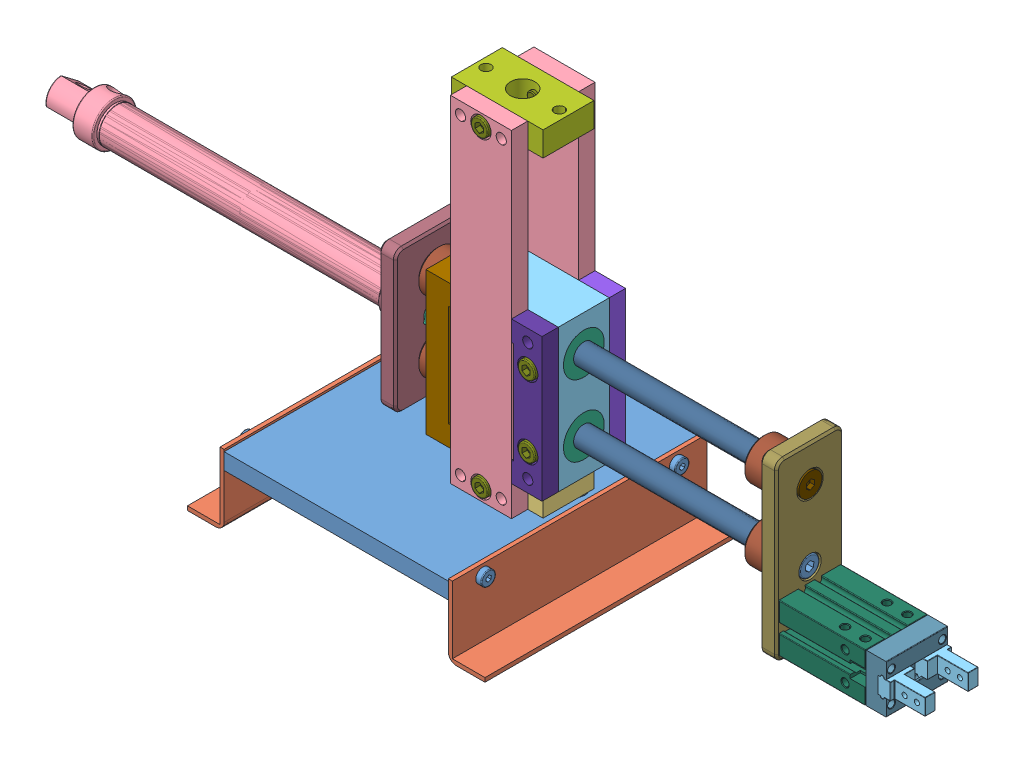
SolidWorks assembly S4, configuration Default. Lengths in mm.
Overall size (436.7 199 125).
52 component instances, 24 part files, 126 mates.
Components (placement in the parent):
- tam de lon-1: tam de lon [Default] at (42.5889 56.6685 101.1963) size (110 8 125)
- khoi do-1: khoi do [Default] at (98.4472 49.4552 163.6963) x (0 0 -1) z (-1 0 0) size (125 35 18)
- khoi do-2: khoi do [Default] at (-13.2695 49.4552 38.6963) x (0 0 1) z (1 0 0) size (125 35 18)
- mieng dem duoi-1: mieng dem duoi [Default] at (71.5889 64.6685 101.1963) size (45 12 25)
- thanh dan huong lon x2-1: thanh dan huong lon x2 [Default] at (71.5889 147.1685 113.6963) x (1 0 0) z (0 -1 0) size (30 8 165)
- thanh dan huong lon x2-2: thanh dan huong lon x2 [Default] at (71.5889 147.1685 88.6963) x (1 0 0) z (0 1 0) size (30 8 165)
- con truot s4 -1: con truot s4  [Default] at (79.0889 79.5805 101.1963) x (-1 0 0) z (0 0 -1) size (45 70 25)
- bac lot-1: bac lot [Default] at (101.5889 97.0805 101.1963) x (0 1 0) z (0 0 1) size (20 12 20)
- bac lot-2: bac lot [Default] at (101.5889 132.0805 101.1963) x (0 1 0) z (0 0 1) size (20 12 20)
- bac lot-3: bac lot [Default] at (56.5889 132.0805 101.1963) x (0 0.381849 -0.924225) z (0 -0.924225 -0.381849) size (20 12 20)
- bac lot-4: bac lot [Default] at (56.5889 97.0805 101.1963) x (0 0.381849 -0.924225) z (0 -0.924225 -0.381849) size (20 12 20)
- mieng dem tren-1: mieng dem tren [Default] at (71.5889 217.6685 101.1963) size (45 12 25)
- thanh dan huong so 2 s4-3: thanh dan huong so 2 s4 [Default] at (94.0889 114.5805 88.6963) x (-1 0 0) z (0 -1 0) size (15 8 70)
- tam dan huong-4: tam dan huong [Default] at (44.5889 114.5805 101.1963) x (0 -1 0) z (0 0 1) size (70 12 41)
- chot dan huong-1: chot dan huong [Default] at (204.5889 132.0805 101.1963) x (0 0.988897 -0.148604) z (0 0.148604 0.988897) size (10 175 10)
- chot dan huong-2: chot dan huong [Default] at (204.5889 97.0805 101.1963) x (0 0.324021 0.94605) z (0 -0.94605 0.324021) size (10 175 10)
- bac chan-1: bac chan [Default] at (204.5889 132.0805 101.1963) x (0 0.942027 0.335537) z (0 -0.335537 0.942027) size (20 15 20)
- bac chan-2: bac chan [Default] at (204.5889 97.0805 101.1963) x (0 1 0) z (0 0 1) size (20 15 20)
- bac chan-3: bac chan [Default] at (44.5889 132.0805 101.1963) x (0 -0.757955 0.652306) z (0 -0.652306 -0.757955) size (20 15 20)
- bac chan-4: bac chan [Default] at (44.5889 97.0805 101.1963) x (0 0.99939 -0.03491) z (0 0.03491 0.99939) size (20 15 20)
- ban canh truoc-1: ban canh truoc [Default] at (204.5889 106.5805 101.1963) x (0 0 -1) z (0 -1 0) size (33 8 86)
- ban canh sau-1: ban canh sau [Default] at (29.5889 114.5805 101.1963) x (0 0 -1) z (0 1 0) size (41 8 70)
- NMHZ2-16D-2: NMHZ2-16D [Default] at (197.6009 76.0227 123.6032) x (0 0 -1) z (1 0 0) size (30.6 23.6 52.5)
  - NMHZ2-16D Slipway-1: NMHZ2-16D Slipway [Default] at (22.4069 2.6078 57.488) size (30.1 23.6 10)
  - NMHZ2-16D cylinder-2: NMHZ2-16D cylinder [Default] at (22.4069 2.6078 14.988) size (30.6 23.6 42.5)
- socket head cap screw_din-2: socket head cap screw_din [DIN 912 M5 x 16 --- 16N] at (94.5889 132.0805 79.8963) x (0 0 1) z (-1 0 0) size (21 8.5 8.5)
- socket head cap screw_din-5: socket head cap screw_din [DIN 912 M5 x 16 --- 16N] at (94.5889 97.0805 79.8963) x (0 0 1) z (-1 0 0) size (21 8.5 8.5)
- socket head cap screw_din-6: socket head cap screw_din [DIN 912 M5 x 16 --- 16N] at (71.5889 70.6685 79.8963) x (0 0 1) z (-1 0 0) size (21 8.5 8.5)
- socket head cap screw_din-9: socket head cap screw_din [DIN 912 M5 x 8 --- 8N] at (71.5889 70.6685 122.4963) x (0 0 -1) z (1 0 0) size (13 8.5 8.5)
- socket head cap screw_din-10: socket head cap screw_din [DIN 912 M5 x 8 --- 8N] at (45.2889 85.5805 108.6963) size (13 8.5 8.5)
- socket head cap screw_din-11: socket head cap screw_din [DIN 912 M5 x 8 --- 8N] at (45.2889 143.5805 93.6963) size (13 8.5 8.5)
- thanh dan huong s4-1: thanh dan huong s4 [Default] at (94.0889 114.5805 113.6963) x (-1 0 0) z (0 1 0) size (15 8 70)
- socket head cap screw_din-13: socket head cap screw_din [DIN 912 M5 x 12 --- 12N] at (94.5889 97.0805 122.4963) x (0 0 -1) z (1 0 0) size (17 8.5 8.5)
- socket head cap screw_din-14: socket head cap screw_din [DIN 912 M5 x 12 --- 12N] at (94.5889 132.0805 122.4963) x (0 0 -1) z (1 0 0) size (17 8.5 8.5)
- socket head cap screw_din-17: socket head cap screw_din [DIN 912 M5 x 12 --- 12N] at (71.5889 223.6685 79.8963) x (0 0 1) z (-0.154025 0.988067 0) size (17 8.5 8.5)
- socket head cap screw_din-18: socket head cap screw_din [DIN 912 M5 x 12 --- 12N] at (71.5889 223.6685 122.4963) x (0 0 -1) z (1 0 0) size (17 8.5 8.5)
- socket csink head cap screw 10642_din-2: socket csink head cap screw 10642_din [EN ISO 10642 - M6 x 8 - 8N] at (21.3689 132.0805 101.1963) x (1 0 0) z (0 0.02259 0.999745) size (8 11.34 11.34)
- socket csink head cap screw 10642_din-3: socket csink head cap screw 10642_din [EN ISO 10642 - M6 x 8 - 8N] at (212.8089 132.0805 101.1963) x (-1 0 0) z (0 -0.022602 -0.999745) size (8 11.34 11.34)
- socket head thin cap screw_din-2: socket head thin cap screw_din [DIN 7984 - M6 x 10 --- 7N] at (212.3889 97.0805 101.1963) x (-1 0 0) z (0 0.924225 0.381849) size (14 10 10)
- socket head thin cap screw_din-4: socket head thin cap screw_din [DIN 7984 - M6 x 10 --- 7N] at (21.7889 97.0805 101.1963) size (14 10 10)
- socket head thin cap screw_din-5: socket head thin cap screw_din [DIN 7984 - M4 x 6 --- 3.9N] at (-17.2111 60.6685 53.6963) size (8.8 7 7)
- socket head thin cap screw_din-6: socket head thin cap screw_din [DIN 7984 - M4 x 6 --- 3.9N] at (-17.2111 60.6685 148.6963) size (8.8 7 7)
- socket head thin cap screw_din-7: socket head thin cap screw_din [DIN 7984 - M4 x 6 --- 3.9N] at (102.3889 60.6685 53.6963) x (-1 0 0) z (0 0.924225 0.381849) size (8.8 7 7)
- socket head thin cap screw_din-8: socket head thin cap screw_din [DIN 7984 - M4 x 6 --- 3.9N] at (102.3889 60.6685 148.6963) x (-1 0 0) z (0 0.924225 0.381849) size (8.8 7 7)
- socket head thin cap screw_din-10: socket head thin cap screw_din [DIN 7984 - M4 x 12 --- 9.9N] at (206.1889 71.2805 112.1963) size (14.8 7 7)
- socket head thin cap screw_din-11: socket head thin cap screw_din [DIN 7984 - M4 x 12 --- 9.9N] at (206.1889 86.2805 90.1963) size (14.8 7 7)
- Rod-1: Rod [Default] at (-92.4392 114.5805 101.1963) x (0 0.871767 -0.48992) z (0 -0.48992 -0.871767) size (6.2 165 6.2)
- Nut 5-1: Nut 5 [Default] at (55.0889 114.5805 101.1963) x (0 0.12782 0.991797) z (0 0.991797 -0.12782) size (11.32 3 9.8)
- 16 X 100 Cylinder bore-2: 16 X 100 Cylinder bore [Default] at (-58.6111 114.5805 101.1963) x (0 0.79605 -0.605231) z (-1 0 0) size (21.5 21.5 192)
- NMHZ2-16D air claw-1: NMHZ2-16D air claw [Default] at (263.0889 78.6305 98.1463) x (0 0 -1) z (1 0 0) size (12 10 21)
- NMHZ2-16D air claw-2: NMHZ2-16D air claw [Default] at (263.0889 78.6305 104.2463) x (0 0 1) z (1 0 0) size (12 10 21)
- hex nut style 2 gradeab_din-2: hex nut style 2 gradeab_din [Hexagon Nut ISO 4033 - M8 - W - N] at (37.0889 114.5805 101.1963) x (0 0.684808 -0.728723) z (1 0 0) size (13 15.01 7.5)
Mates (geometry in assembly coordinates):
- Parallel1: parallel anti-aligned: plane of tam de lon-1 through (42.5889 64.6685 101.1963) normal (0 1 0); plane of khoi do-1 through (97.5889 30.6685 38.6963) normal (0 -1 0)
- Parallel2: parallel anti-aligned: plane of tam de lon-1 through (97.5889 64.6685 38.6963) normal (1 0 0); plane of khoi do-1 through (97.5889 30.6685 38.6963) normal (-1 0 0)
- Concentric1: concentric aligned: cylinder of tam de lon-1 through (82.5889 60.6685 53.6963) axis (1 0 0) radius 2.5; cylinder of khoi do-1 through (-25.4111 60.6685 53.6963) axis (1 0 0) radius 2.5
- Coincident1: coincident anti-aligned: plane of tam de lon-1 through (97.5889 64.6685 38.6963) normal (1 0 0); plane of khoi do-1 through (97.5889 30.6685 38.6963) normal (-1 0 0)
- Parallel3: parallel anti-aligned: plane of tam de lon-1 through (42.5889 64.6685 101.1963) normal (0 1 0); plane of khoi do-2 through (-12.4111 30.6685 163.6963) normal (0 -1 0)
- Parallel4: parallel anti-aligned: plane of tam de lon-1 through (-12.4111 64.6685 38.6963) normal (-1 0 0); plane of khoi do-2 through (-12.4111 30.6685 163.6963) normal (1 0 0)
- Concentric2: concentric aligned: cylinder of tam de lon-1 through (2.5889 60.6685 148.6963) axis (-1 0 0) radius 2.5; cylinder of khoi do-2 through (110.5889 60.6685 148.6963) axis (-1 0 0) radius 2.5
- Coincident2: coincident anti-aligned: plane of tam de lon-1 through (-12.4111 64.6685 38.6963) normal (-1 0 0); plane of khoi do-2 through (-12.4111 30.6685 163.6963) normal (1 0 0)
- Concentric3: concentric aligned: cylinder of tam de lon-1 through (89.5889 56.6685 93.6963) axis (0 1 0) radius 2.75; cylinder of mieng dem duoi-1 through (89.5889 64.6685 93.6963) axis (0 1 0) radius 2.5
- Concentric4: concentric aligned: cylinder of tam de lon-1 through (53.5889 56.6685 108.6963) axis (0 1 0) radius 2.75; cylinder of mieng dem duoi-1 through (53.5889 64.6685 108.6963) axis (0 1 0) radius 2.5
- Coincident3: coincident anti-aligned: plane of tam de lon-1 through (42.5889 64.6685 101.1963) normal (0 1 0); plane of mieng dem duoi-1 through (71.5889 64.6685 101.1963) normal (0 -1 0)
- Parallel6: parallel anti-aligned: plane of mieng dem duoi-1 through (71.5889 76.6685 101.1963) normal (0 1 0); plane of thanh dan huong lon x2-1 through (56.5889 64.6685 121.6963) normal (0 -1 0)
- Parallel7: parallel anti-aligned: plane of mieng dem duoi-1 through (49.0889 76.6685 113.6963) normal (0 0 1); plane of thanh dan huong lon x2-1 through (71.5889 147.1685 113.6963) normal (0 0 -1)
- Concentric5: concentric anti-aligned: cylinder of mieng dem duoi-1 through (81.5889 70.6685 160.6963) axis (0 0 -1) radius 2.5; cylinder of thanh dan huong lon x2-1 through (81.5889 70.6685 80.4963) axis (0 0 1) radius 2.5
- Coincident4: coincident anti-aligned: plane of mieng dem duoi-1 through (49.0889 76.6685 113.6963) normal (0 0 1); plane of thanh dan huong lon x2-1 through (71.5889 147.1685 113.6963) normal (0 0 -1)
- Parallel8: parallel anti-aligned: plane of mieng dem duoi-1 through (71.5889 76.6685 101.1963) normal (0 1 0); plane of thanh dan huong lon x2-2 through (56.5889 64.6685 80.6963) normal (0 -1 0)
- Parallel9: parallel anti-aligned: plane of mieng dem duoi-1 through (49.0889 76.6685 88.6963) normal (0 0 -1); plane of thanh dan huong lon x2-2 through (71.5889 147.1685 88.6963) normal (0 0 1)
- Concentric6: concentric aligned: cylinder of mieng dem duoi-1 through (81.5889 70.6685 160.6963) axis (0 0 -1) radius 2.5; cylinder of thanh dan huong lon x2-2 through (81.5889 70.6685 121.8963) axis (0 0 -1) radius 2.5
- Coincident5: coincident anti-aligned: plane of mieng dem duoi-1 through (49.0889 76.6685 88.6963) normal (0 0 -1); plane of thanh dan huong lon x2-2 through (71.5889 147.1685 88.6963) normal (0 0 1)
- Parallel10: parallel anti-aligned: plane of mieng dem duoi-1 through (94.0889 76.6685 88.6963) normal (1 0 0); plane of con truot s4 -1 through (56.5889 149.5805 113.6963) normal (-1 0 0)
- Parallel11: parallel aligned: plane of mieng dem duoi-1 through (71.5889 76.6685 101.1963) normal (0 1 0); plane of con truot s4 -1 through (79.0889 149.5805 101.1963) normal (0 1 0)
- Coincident6: coincident anti-aligned: plane of thanh dan huong lon x2-2 through (71.5889 147.1685 88.6963) normal (0 0 1); plane of con truot s4 -1 through (101.5889 149.5805 88.6963) normal (0 0 -1)
- Concentric7: concentric anti-aligned: cylinder of con truot s4 -1 through (126.5889 97.0805 101.1963) axis (-1 0 0) radius 6; cylinder of bac lot-1 through (89.5889 97.0805 101.1963) axis (1 0 0) radius 6
- Coincident14: coincident anti-aligned: plane of con truot s4 -1 through (99.5889 97.0805 101.1963) normal (1 0 0); plane of bac lot-1 through (99.5889 97.0805 101.1963) normal (-1 0 0)
- Concentric8: concentric anti-aligned: cylinder of con truot s4 -1 through (126.5889 132.0805 101.1963) axis (-1 0 0) radius 6; cylinder of bac lot-2 through (89.5889 132.0805 101.1963) axis (1 0 0) radius 6
- Coincident15: coincident anti-aligned: plane of con truot s4 -1 through (99.5889 132.0805 101.1963) normal (1 0 0); plane of bac lot-2 through (99.5889 132.0805 101.1963) normal (-1 0 0)
- Concentric9: concentric aligned: cylinder of con truot s4 -1 through (126.5889 132.0805 101.1963) axis (-1 0 0) radius 6; cylinder of bac lot-3 through (68.5889 132.0805 101.1963) axis (-1 0 0) radius 6
- Coincident16: coincident anti-aligned: plane of con truot s4 -1 through (58.5889 132.0805 101.1963) normal (-1 0 0); plane of bac lot-3 through (58.5889 132.0805 101.1963) normal (1 0 0)
- Concentric10: concentric aligned: cylinder of con truot s4 -1 through (126.5889 97.0805 101.1963) axis (-1 0 0) radius 6; cylinder of bac lot-4 through (68.5889 97.0805 101.1963) axis (-1 0 0) radius 6
- Coincident18: coincident anti-aligned: plane of con truot s4 -1 through (58.5889 97.0805 101.1963) normal (-1 0 0); plane of bac lot-4 through (58.5889 97.0805 101.1963) normal (1 0 0)
- Parallel23: parallel aligned: plane of thanh dan huong lon x2-2 through (56.5889 229.6685 80.6963) normal (0 1 0); plane of mieng dem tren-1 through (71.5889 229.6685 101.1963) normal (0 1 0)
- Concentric12: concentric aligned: cylinder of thanh dan huong lon x2-2 through (61.5889 223.6685 121.8963) axis (0 0 -1) radius 2.5; cylinder of mieng dem tren-1 through (61.5889 223.6685 160.6963) axis (0 0 -1) radius 2.5
- Coincident21: coincident anti-aligned: plane of thanh dan huong lon x2-2 through (71.5889 147.1685 88.6963) normal (0 0 1); plane of mieng dem tren-1 through (49.0889 229.6685 88.6963) normal (0 0 -1)
- Parallel38: parallel aligned: plane of con truot s4 -1 through (79.0889 149.5805 101.1963) normal (0 1 0); plane of thanh dan huong so 2 s4-3 through (101.5889 149.5805 80.6963) normal (0 1 0)
- Parallel39: parallel anti-aligned: plane of con truot s4 -1 through (101.5889 149.5805 88.6963) normal (0 0 -1); plane of thanh dan huong so 2 s4-3 through (94.0889 114.5805 88.6963) normal (0 0 1)
- Coincident32: coincident aligned: plane of con truot s4 -1 through (79.0889 149.5805 101.1963) normal (0 1 0); plane of thanh dan huong so 2 s4-3 through (101.5889 149.5805 80.6963) normal (0 1 0)
- Coincident33: coincident aligned: plane of con truot s4 -1 through (101.5889 149.5805 113.6963) normal (1 0 0); plane of thanh dan huong so 2 s4-3 through (101.5889 149.5805 80.6963) normal (1 0 0)
- Coincident34: coincident anti-aligned: plane of con truot s4 -1 through (101.5889 149.5805 88.6963) normal (0 0 -1); plane of thanh dan huong so 2 s4-3 through (94.0889 114.5805 88.6963) normal (0 0 1)
- Coincident36: coincident anti-aligned: plane of thanh dan huong lon x2-2 through (86.5889 64.6685 80.6963) normal (1 0 0); plane of thanh dan huong so 2 s4-3 through (86.5889 149.5805 80.6963) normal (-1 0 0)
- Parallel46: parallel aligned: plane of con truot s4 -1 through (79.0889 149.5805 101.1963) normal (0 1 0); plane of tam dan huong-4 through (56.5889 149.5805 80.6963) normal (0 1 0)
- Parallel47: parallel anti-aligned: plane of con truot s4 -1 through (56.5889 149.5805 113.6963) normal (-1 0 0); plane of tam dan huong-4 through (55.5889 139.5805 33.6963) normal (1 0 0)
- Coincident40: coincident anti-aligned: plane of con truot s4 -1 through (56.5889 149.5805 113.6963) normal (-1 0 0); plane of tam dan huong-4 through (56.5889 114.5805 101.1963) normal (1 0 0)
- Concentric29: concentric aligned: cylinder of con truot s4 -1 through (71.5889 143.5805 93.6963) axis (-1 0 0) radius 2.5; cylinder of tam dan huong-4 through (132.5889 143.5805 93.6963) axis (-1 0 0) radius 2.75
- Concentric41: concentric anti-aligned: cylinder of bac lot-2 through (116.5889 132.0805 101.1963) axis (-1 0 0) radius 5; cylinder of chot dan huong-1 through (-68.4111 132.0805 101.1963) axis (1 0 0) radius 5
- Concentric42: concentric anti-aligned: cylinder of bac lot-1 through (116.5889 97.0805 101.1963) axis (-1 0 0) radius 5; cylinder of chot dan huong-2 through (-68.4111 97.0805 101.1963) axis (1 0 0) radius 5
- Concentric43: concentric anti-aligned: cylinder of chot dan huong-1 through (-68.4111 132.0805 101.1963) axis (1 0 0) radius 5; cylinder of bac chan-1 through (204.5889 132.0805 101.1963) axis (-1 0 0) radius 5
- Coincident53: coincident aligned: plane of chot dan huong-1 through (204.5889 132.0805 101.1963) normal (1 0 0); plane of bac chan-1 through (204.5889 132.0805 101.1963) normal (1 0 0)
- Concentric44: concentric anti-aligned: cylinder of chot dan huong-2 through (-68.4111 97.0805 101.1963) axis (1 0 0) radius 5; cylinder of bac chan-2 through (204.5889 97.0805 101.1963) axis (-1 0 0) radius 5
- Coincident54: coincident aligned: plane of chot dan huong-2 through (204.5889 97.0805 101.1963) normal (1 0 0); plane of bac chan-2 through (204.5889 97.0805 101.1963) normal (1 0 0)
- Concentric45: concentric anti-aligned: cylinder of chot dan huong-1 through (-68.4111 132.0805 101.1963) axis (1 0 0) radius 5; cylinder of bac chan-3 through (44.5889 132.0805 101.1963) axis (-1 0 0) radius 5
- Coincident55: coincident aligned: plane of chot dan huong-1 through (29.5889 132.0805 101.1963) normal (-1 0 0); plane of bac chan-3 through (29.5889 132.0805 101.1963) normal (-1 0 0)
- Coincident57: coincident aligned: plane of chot dan huong-2 through (29.5889 97.0805 101.1963) normal (-1 0 0); plane of bac chan-4 through (29.5889 97.0805 101.1963) normal (-1 0 0)
- Concentric47: concentric aligned: cylinder of chot dan huong-1 through (184.5889 132.0805 101.1963) axis (1 0 0) radius 3; cylinder of ban canh truoc-1 through (204.5889 132.0805 101.1963) axis (1 0 0) radius 3.3
- Concentric48: concentric aligned: cylinder of chot dan huong-2 through (184.5889 97.0805 101.1963) axis (1 0 0) radius 3; cylinder of ban canh truoc-1 through (204.5889 97.0805 101.1963) axis (1 0 0) radius 3.3
- Coincident58: coincident anti-aligned: plane of chot dan huong-1 through (204.5889 132.0805 101.1963) normal (1 0 0); plane of ban canh truoc-1 through (204.5889 106.5805 101.1963) normal (-1 0 0)
- Coincident59: coincident anti-aligned: plane of chot dan huong-2 through (204.5889 97.0805 101.1963) normal (1 0 0); plane of ban canh truoc-1 through (204.5889 106.5805 101.1963) normal (-1 0 0)
- Concentric49: concentric aligned: cylinder of chot dan huong-1 through (49.5889 132.0805 101.1963) axis (-1 0 0) radius 3; cylinder of ban canh sau-1 through (29.5889 132.0805 101.1963) axis (-1 0 0) radius 3.3
- Concentric50: concentric aligned: cylinder of chot dan huong-2 through (49.5889 97.0805 101.1963) axis (-1 0 0) radius 3; cylinder of ban canh sau-1 through (29.5889 97.0805 101.1963) axis (-1 0 0) radius 3.3
- Coincident60: coincident anti-aligned: plane of chot dan huong-1 through (29.5889 132.0805 101.1963) normal (-1 0 0); plane of ban canh sau-1 through (29.5889 114.5805 101.1963) normal (1 0 0)
- Coincident61: coincident anti-aligned: plane of chot dan huong-2 through (29.5889 97.0805 101.1963) normal (-1 0 0); plane of ban canh sau-1 through (29.5889 114.5805 101.1963) normal (1 0 0)
- Concentric55: concentric anti-aligned: cylinder of ban canh truoc-1 through (204.5889 71.2805 112.1963) axis (1 0 0) radius 2.25; cylinder of NMHZ2-16D-2/NMHZ2-16D cylinder-2 through (227.5889 71.2805 112.1963) axis (-1 0 0) radius 2
- Concentric56: concentric anti-aligned: cylinder of ban canh truoc-1 through (204.5889 86.2805 90.1963) axis (1 0 0) radius 2.25; cylinder of NMHZ2-16D-2/NMHZ2-16D cylinder-2 through (227.5889 86.2805 90.1963) axis (-1 0 0) radius 2
- Coincident62: coincident anti-aligned: plane of ban canh truoc-1 through (212.5889 106.5805 101.1963) normal (1 0 0); plane of NMHZ2-16D-2/NMHZ2-16D cylinder-2 through (212.5889 78.6305 101.1963) normal (-1 0 0)
- Concentric57: concentric anti-aligned: cylinder of chot dan huong-2 through (-68.4111 97.0805 101.1963) axis (1 0 0) radius 5; cylinder of bac chan-4 through (44.5889 97.0805 101.1963) axis (-1 0 0) radius 5
- Concentric61: concentric aligned: cylinder of thanh dan huong so 2 s4-3 through (94.5889 132.0805 88.6963) axis (0 0 -1) radius 2.75; cylinder of socket head cap screw_din-2 through (94.5889 132.0805 48.1463) axis (0 0 -1) radius 4.25
- Coincident66: coincident anti-aligned: plane of thanh dan huong so 2 s4-3 through (94.5889 132.0805 84.8963) normal (0 0 -1); plane of socket head cap screw_din-2 through (94.5889 136.3305 84.8963) normal (0 0 1)
- Concentric64: concentric aligned: cylinder of thanh dan huong so 2 s4-3 through (94.5889 97.0805 88.6963) axis (0 0 -1) radius 2.75; cylinder of socket head cap screw_din-5 through (94.5889 97.0805 48.1463) axis (0 0 -1) radius 4.25
- Coincident69: coincident anti-aligned: plane of thanh dan huong so 2 s4-3 through (94.5889 97.0805 84.8963) normal (0 0 -1); plane of socket head cap screw_din-5 through (94.5889 101.3305 84.8963) normal (0 0 1)
- Concentric651: concentric aligned: cylinder of thanh dan huong lon x2-2 through (71.5889 70.6685 88.6963) axis (0 0 -1) radius 2.75; cylinder of socket head cap screw_din-6 through (71.5889 70.6685 48.1463) axis (0 0 -1) radius 4.25
- Coincident701: coincident anti-aligned: plane of thanh dan huong lon x2-2 through (71.5889 70.6685 84.8963) normal (0 0 -1); plane of socket head cap screw_din-6 through (71.5889 74.9185 84.8963) normal (0 0 1)
- Concentric66: concentric aligned: cylinder of thanh dan huong lon x2-1 through (71.5889 70.6685 113.6963) axis (0 0 1) radius 2.75; cylinder of socket head cap screw_din-9 through (71.5889 70.6685 154.2463) axis (0 0 1) radius 4.25
- Coincident71: coincident anti-aligned: plane of thanh dan huong lon x2-1 through (71.5889 70.6685 117.4963) normal (0 0 1); plane of socket head cap screw_din-9 through (71.5889 74.9185 117.4963) normal (0 0 -1)
- Concentric67: concentric aligned: cylinder of tam dan huong-4 through (132.5889 85.5805 108.6963) axis (-1 0 0) radius 2.75; cylinder of socket head cap screw_din-10 through (13.5389 85.5805 108.6963) axis (-1 0 0) radius 4.25
- Coincident72: coincident anti-aligned: plane of tam dan huong-4 through (50.2889 85.5805 108.6963) normal (-1 0 0); plane of socket head cap screw_din-10 through (50.2889 89.8305 108.6963) normal (1 0 0)
- Concentric68: concentric aligned: cylinder of tam dan huong-4 through (132.5889 143.5805 93.6963) axis (-1 0 0) radius 2.75; cylinder of socket head cap screw_din-11 through (13.5389 143.5805 93.6963) axis (-1 0 0) radius 4.25
- Coincident73: coincident anti-aligned: plane of tam dan huong-4 through (50.2889 143.5805 93.6963) normal (-1 0 0); plane of socket head cap screw_din-11 through (50.2889 147.8305 93.6963) normal (1 0 0)
- Parallel62: parallel aligned: plane of con truot s4 -1 through (101.5889 149.5805 113.6963) normal (0 0 1); plane of thanh dan huong s4-1 through (94.0889 114.5805 121.6963) normal (0 0 1)
- Parallel63: parallel aligned: plane of con truot s4 -1 through (101.5889 149.5805 113.6963) normal (1 0 0); plane of thanh dan huong s4-1 through (101.5889 79.5805 121.6963) normal (1 0 0)
- Concentric71: concentric anti-aligned: cylinder of con truot s4 -1 through (94.5889 97.0805 124.6963) axis (0 0 -1) radius 2.5; cylinder of thanh dan huong s4-1 through (94.5889 97.0805 113.6963) axis (0 0 1) radius 2.75
- Coincident76: coincident anti-aligned: plane of con truot s4 -1 through (101.5889 149.5805 113.6963) normal (0 0 1); plane of thanh dan huong s4-1 through (94.0889 114.5805 113.6963) normal (0 0 -1)
- Concentric72: concentric aligned: cylinder of thanh dan huong s4-1 through (94.5889 97.0805 113.6963) axis (0 0 1) radius 2.75; cylinder of socket head cap screw_din-13 through (94.5889 97.0805 154.2463) axis (0 0 1) radius 4.25
- Coincident77: coincident anti-aligned: plane of thanh dan huong s4-1 through (94.5889 97.0805 117.4963) normal (0 0 1); plane of socket head cap screw_din-13 through (94.5889 101.3305 117.4963) normal (0 0 -1)
- Concentric73: concentric aligned: cylinder of thanh dan huong s4-1 through (94.5889 132.0805 113.6963) axis (0 0 1) radius 2.75; cylinder of socket head cap screw_din-14 through (94.5889 132.0805 154.2463) axis (0 0 1) radius 4.25
- Coincident78: coincident anti-aligned: plane of thanh dan huong s4-1 through (94.5889 132.0805 117.4963) normal (0 0 1); plane of socket head cap screw_din-14 through (94.5889 136.3305 117.4963) normal (0 0 -1)
- Concentric76: concentric aligned: cylinder of thanh dan huong lon x2-2 through (71.5889 223.6685 84.8963) axis (0 0 -1) radius 5; cylinder of socket head cap screw_din-17 through (71.5889 223.6685 48.1463) axis (0 0 -1) radius 4.25
- Coincident81: coincident anti-aligned: plane of thanh dan huong lon x2-2 through (71.5889 223.6685 84.8963) normal (0 0 -1); plane of socket head cap screw_din-17 through (75.7882 224.3231 84.8963) normal (0 0 1)
- Concentric77: concentric aligned: cylinder of thanh dan huong lon x2-1 through (71.5889 223.6685 113.6963) axis (0 0 1) radius 2.75; cylinder of socket head cap screw_din-18 through (71.5889 223.6685 154.2463) axis (0 0 1) radius 4.25
- Coincident82: coincident anti-aligned: plane of thanh dan huong lon x2-1 through (71.5889 223.6685 117.4963) normal (0 0 1); plane of socket head cap screw_din-18 through (71.5889 227.9185 117.4963) normal (0 0 -1)
- Coincident83: coincident aligned: cone of ban canh sau-1 through (24.7889 132.0805 101.1963) axis (1 0 0); cone of socket csink head cap screw 10642_din-2 through (22.4189 132.0805 101.1963) axis (1 0 0)
- Coincident84: coincident aligned: cone of ban canh truoc-1 through (209.3889 132.0805 101.1963) axis (-1 0 0); cone of socket csink head cap screw 10642_din-3 through (211.7589 132.0805 101.1963) axis (-1 0 0)
- Concentric78: concentric aligned: cylinder of ban canh truoc-1 through (204.5889 97.0805 101.1963) axis (1 0 0) radius 3.3; cylinder of socket head thin cap screw_din-2 through (244.1389 97.0805 101.1963) axis (1 0 0) radius 5
- Coincident85: coincident anti-aligned: plane of ban canh truoc-1 through (208.3889 97.0805 101.1963) normal (1 0 0); plane of socket head thin cap screw_din-2 through (208.3889 95.1713 105.8174) normal (-1 0 0)
- Concentric79: concentric aligned: cylinder of ban canh sau-1 through (29.5889 97.0805 101.1963) axis (-1 0 0) radius 3.3; cylinder of socket head thin cap screw_din-4 through (-9.9611 97.0805 101.1963) axis (-1 0 0) radius 5
- Coincident86: coincident anti-aligned: plane of ban canh sau-1 through (25.7889 97.0805 101.1963) normal (-1 0 0); plane of socket head thin cap screw_din-4 through (25.7889 102.0805 101.1963) normal (1 0 0)
- Concentric80: concentric aligned: cylinder of khoi do-2 through (110.5889 60.6685 53.6963) axis (-1 0 0) radius 2.5; cylinder of socket head thin cap screw_din-5 through (-48.9611 60.6685 53.6963) axis (-1 0 0) radius 3.5
- Coincident87: coincident anti-aligned: plane of khoi do-2 through (-14.4111 32.6685 163.6963) normal (-1 0 0); plane of socket head thin cap screw_din-5 through (-14.4111 64.1685 53.6963) normal (1 0 0)
- Concentric81: concentric aligned: cylinder of khoi do-2 through (110.5889 60.6685 148.6963) axis (-1 0 0) radius 2.5; cylinder of socket head thin cap screw_din-6 through (-48.9611 60.6685 148.6963) axis (-1 0 0) radius 3.5
- Coincident88: coincident anti-aligned: plane of khoi do-2 through (-14.4111 32.6685 163.6963) normal (-1 0 0); plane of socket head thin cap screw_din-6 through (-14.4111 64.1685 148.6963) normal (1 0 0)
- Concentric82: concentric aligned: cylinder of khoi do-1 through (-25.4111 60.6685 53.6963) axis (1 0 0) radius 2.5; cylinder of socket head thin cap screw_din-7 through (134.1389 60.6685 53.6963) axis (1 0 0) radius 3.5
- Coincident89: coincident anti-aligned: plane of khoi do-1 through (99.5889 32.6685 38.6963) normal (1 0 0); plane of socket head thin cap screw_din-7 through (99.5889 59.332 56.9311) normal (-1 0 0)
- Concentric83: concentric aligned: cylinder of khoi do-1 through (-25.4111 60.6685 148.6963) axis (1 0 0) radius 2.5; cylinder of socket head thin cap screw_din-8 through (134.1389 60.6685 148.6963) axis (1 0 0) radius 3.5
- Coincident90: coincident anti-aligned: plane of khoi do-1 through (99.5889 32.6685 38.6963) normal (1 0 0); plane of socket head thin cap screw_din-8 through (99.5889 59.332 151.9311) normal (-1 0 0)
- Concentric84: concentric anti-aligned: cylinder of ban canh truoc-1 through (204.5889 71.2805 112.1963) axis (1 0 0) radius 2.25; cylinder of socket head thin cap screw_din-10 through (174.4389 71.2805 112.1963) axis (-1 0 0) radius 3.5
- Coincident91: coincident anti-aligned: plane of ban canh truoc-1 through (208.9889 71.2805 112.1963) normal (-1 0 0); plane of socket head thin cap screw_din-10 through (208.9889 74.7805 112.1963) normal (1 0 0)
- Concentric85: concentric aligned: cylinder of ban canh truoc-1 through (208.9889 86.2805 90.1963) axis (-1 0 0) radius 4; cylinder of socket head thin cap screw_din-11 through (174.4389 86.2805 90.1963) axis (-1 0 0) radius 3.5
- Coincident92: coincident anti-aligned: plane of ban canh truoc-1 through (208.9889 86.2805 90.1963) normal (-1 0 0); plane of socket head thin cap screw_din-11 through (208.9889 89.7805 90.1963) normal (1 0 0)
- LimitDistance3: limit distance = 88 mm anti-aligned: plane of bac chan-1 through (189.5889 132.0805 101.1963) normal (-1 0 0); plane of con truot s4 -1 through (101.5889 149.5805 113.6963) normal (1 0 0)
- LimitDistance4: limit distance = 68.0879 mm anti-aligned: plane of tam dan huong-4 through (56.5889 149.5805 80.6963) normal (0 1 0); plane of mieng dem tren-1 through (71.5889 217.6685 101.1963) normal (0 -1 0)
- Concentric93: concentric anti-aligned: cylinder of con truot s4 -1 through (71.5889 114.5805 101.1963) axis (-1 0 0) radius 2.5; cylinder of Rod-1 through (52.5608 114.5805 101.1963) axis (1 0 0) radius 2.6
- Concentric94: concentric anti-aligned: cylinder of Rod-1 through (52.5608 114.5805 101.1963) axis (1 0 0) radius 2.6; cylinder of Nut 5-1 through (56.5889 114.5805 101.1963) axis (-1 0 0) radius 2.75
- Lock4: lock: unknown of Rod-1; unknown of Nut 5-1
- Coincident99: coincident anti-aligned: plane of con truot s4 -1 through (56.5889 149.5805 113.6963) normal (-1 0 0); plane of Nut 5-1 through (56.5889 114.5805 101.1963) normal (1 0 0)
- Concentric95: concentric anti-aligned: cylinder of Rod-1 through (72.5608 114.5805 101.1963) axis (-1 0 0) radius 3.1; cylinder of 16 X 100 Cylinder bore-2 through (-137.6111 114.5805 101.1963) axis (1 0 0) radius 3.25
- LimitDistance9: limit distance = 36.1719 mm anti-aligned: plane of Rod-1 through (-92.4392 114.5805 101.1963) normal (-1 0 0); plane of 16 X 100 Cylinder bore-2 through (-128.6111 114.5805 101.1963) normal (1 0 0)
- Parallel64: parallel anti-aligned: plane of NMHZ2-16D-2/NMHZ2-16D Slipway-1 through (261.0889 78.6305 123.6963) normal (1 0 0); plane of NMHZ2-16D air claw-1 through (261.0889 78.6305 86.1463) normal (-1 0 0)
- Coincident105: coincident anti-aligned: plane of NMHZ2-16D-2/NMHZ2-16D Slipway-1 through (261.0889 78.6305 123.6963) normal (1 0 0); plane of NMHZ2-16D air claw-1 through (261.0889 78.6305 86.1463) normal (-1 0 0)
- Concentric97: concentric anti-aligned: cylinder of NMHZ2-16D-2/NMHZ2-16D Slipway-1 through (263.0889 82.6305 123.6963) axis (0 0 -1) radius 1; cylinder of NMHZ2-16D air claw-1 through (263.0889 82.6305 86.1463) axis (0 0 1) radius 1
- Parallel65: parallel anti-aligned: plane of NMHZ2-16D-2/NMHZ2-16D Slipway-1 through (261.0889 78.6305 123.6963) normal (1 0 0); plane of NMHZ2-16D air claw-2 through (261.0889 78.6305 116.2463) normal (-1 0 0)
- Parallel66: parallel anti-aligned: plane of NMHZ2-16D air claw-1 through (263.0889 82.6305 86.1463) normal (0 1 0); plane of NMHZ2-16D air claw-2 through (263.0889 74.6305 116.2463) normal (0 -1 0)
- Coincident106: coincident anti-aligned: plane of NMHZ2-16D-2/NMHZ2-16D Slipway-1 through (261.0889 78.6305 123.6963) normal (1 0 0); plane of NMHZ2-16D air claw-2 through (261.0889 78.6305 116.2463) normal (-1 0 0)
- Concentric98: concentric aligned: cylinder of NMHZ2-16D-2/NMHZ2-16D Slipway-1 through (263.0889 82.6305 123.6963) axis (0 0 -1) radius 1; cylinder of NMHZ2-16D air claw-2 through (263.0889 82.6305 116.2463) axis (0 0 -1) radius 1
- Coincident107: coincident aligned: plane of NMHZ2-16D-2/NMHZ2-16D Slipway-1 through (265.0889 96.1218 86.1463) normal (0 0 -1); plane of NMHZ2-16D air claw-1 through (263.0889 78.6305 86.1463) normal (0 0 -1)
- Coincident108: coincident aligned: plane of NMHZ2-16D-2/NMHZ2-16D Slipway-1 through (265.0889 96.1218 116.2463) normal (0 0 1); plane of NMHZ2-16D air claw-2 through (263.0889 78.6305 116.2463) normal (0 0 1)
- Coincident702: coincident anti-aligned: plane of ban canh sau-1 through (25.5889 114.5805 101.1963) normal (-1 0 0); plane of 16 X 100 Cylinder bore-2 through (25.5889 114.5805 101.1963) normal (1 0 0)
- Concentric652: concentric aligned: cylinder of 16 X 100 Cylinder bore-2 through (-21.236 114.5805 101.1963) axis (1 0 0) radius 5; cylinder of hex nut style 2 gradeab_din-2 through (12.0514 114.5805 101.1963) axis (1 0 0) radius 4
- Coincident703: coincident anti-aligned: plane of ban canh sau-1 through (29.5889 114.5805 101.1963) normal (1 0 0); plane of hex nut style 2 gradeab_din-2 through (29.5889 105.678 110.6697) normal (-1 0 0)
